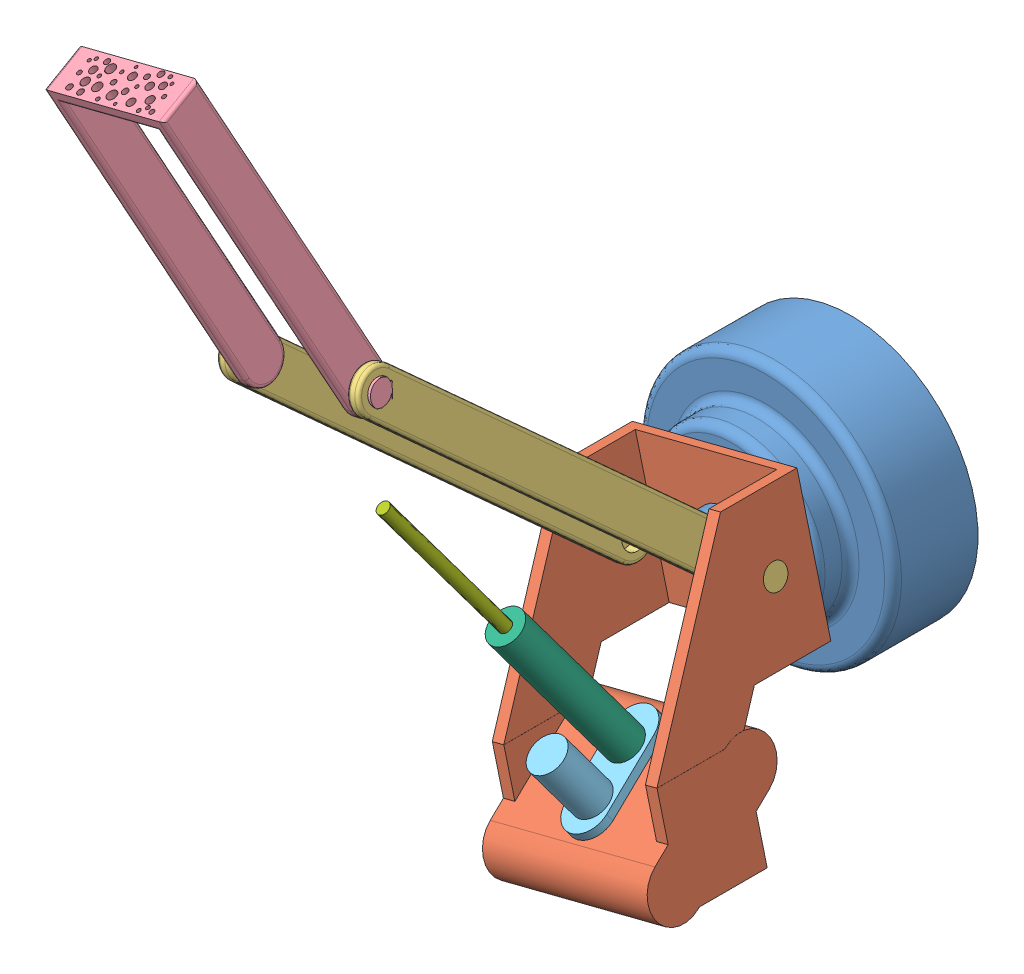
SolidWorks assembly Assem1, configuration Default. Lengths in mm.
Overall size (204.57 472.01 358.29).
7 component instances, 7 part files, 12 mates.
Components (placement in the parent):
- np2-2: np2 [Default] at (-105.9015 111.1219 -48.6119) size (150 150 85)
- Part1-2: Part1 [Default] at (-76.0624 0.0539 119.0843) x (-0.969057 -0.246838 0) z (0.246838 -0.969057 0) size (100.07 123.98 163.69)
- np3-1: np3 [Default] at (-168.413 182.331 136.0596) x (-0.166736 0.654585 0.737372) z (0.969057 0.246838 0) size (275 25 100)
- np4-1: np4 [Default] at (-202.055 342.7642 261.1904) x (-0.227144 0.891739 0.391418) z (0.969057 0.246838 0) size (194.5 25 86)
- asnp1-1: asnp1 [Default] at (-84.2951 32.3747 103.277) x (0.136037 -0.534066 0.834427) z (-0.205968 0.808607 0.551119) size (65 25 50)
- np5-1: np5 [Default] at (-88.11 47.3513 98.0224) x (0.961514 0.062574 0.267535) z (-0.205968 0.808607 0.551119) size (20 20 98)
- np6-1: np6 [Default] at (-127.8619 203.4124 204.3883) x (-0.211884 0.512982 -0.831838) z (0.205968 -0.808607 -0.551119) size (15 15 120)
Mates (geometry in assembly coordinates):
- Coincident4: coincident anti-aligned: plane of Part1-2 through (-119.1854 -10.9304 119.0843) normal (0.969057 0.246838 0); plane of np3-1 through (-147.571 100.5078 43.8881) normal (-0.969057 -0.246838 0)
- Coincident5: coincident anti-aligned: plane of np3-1 through (-140.7876 102.2357 43.8881) normal (0.969057 0.246838 0); plane of np4-1 through (-222.3124 422.2922 309.6821) normal (-0.969057 -0.246838 0)
- Concentric4: concentric aligned: cylinder of np3-1 through (-188.9633 263.0092 226.9414) axis (0.969057 0.246838 0) radius 7; cylinder of np4-1 through (-188.9633 263.0092 226.9414) axis (0.969057 0.246838 0) radius 7
- Concentric8: concentric aligned: cylinder of np5-1 through (-107.265 122.5518 149.2764) axis (-0.205968 0.808607 0.551119) radius 3.5; cylinder of np6-1 through (-107.265 122.5518 149.2764) axis (-0.205968 0.808607 0.551119) radius 3.5
- LimitDistance1: limit distance = 0 mm anti-aligned: plane of np6-1 through (-107.265 122.5518 149.2764) normal (-0.205968 0.808607 0.551119); plane of np5-1 through (-107.265 122.5518 149.2764) normal (0.205968 -0.808607 -0.551119)
- Coincident19: coincident aligned: circle of asnp1-1; circle of np5-1
- Concentric17: concentric anti-aligned: cylinder of np2-2 through (-105.9015 111.1219 36.3881) axis (0 0 -1) radius 15; cylinder of Part1-2 through (-105.9015 111.1219 21.3881) axis (0 0 1) radius 15
- Coincident22: coincident anti-aligned: plane of np2-2 through (-105.9015 111.1219 21.3881) normal (0 0 1); plane of Part1-2 through (-76.0624 0.0539 21.3881) normal (0 0 -1)
- Concentric18: concentric anti-aligned: cylinder of Part1-2 through (-154.3543 98.78 43.8881) axis (0.969057 0.246838 0) radius 7; cylinder of np3-1 through (-57.4487 123.4638 43.8881) axis (-0.969057 -0.246838 0) radius 7
- Coincident26: coincident anti-aligned: plane of Part1-2 through (-87.0159 43.056 86.5884) normal (-0.205968 0.808607 0.551119); plane of asnp1-1 through (-87.0159 43.056 86.5884) normal (0.205968 -0.808607 -0.551119)
- Concentric20: concentric anti-aligned: cylinder of Part1-2 through (-81.5744 21.6934 119.9655) axis (-0.205968 0.808607 0.551119) radius 12.5; cylinder of asnp1-1 through (-82.6042 25.7365 122.7211) axis (0.205968 -0.808607 -0.551119) radius 12.5
- Coincident27: coincident anti-aligned: plane of Part1-2 through (-74.9027 46.1415 86.5884) normal (-0.969057 -0.246838 0); plane of asnp1-1 through (-75.9325 50.1846 89.344) normal (0.969057 0.246838 0)
